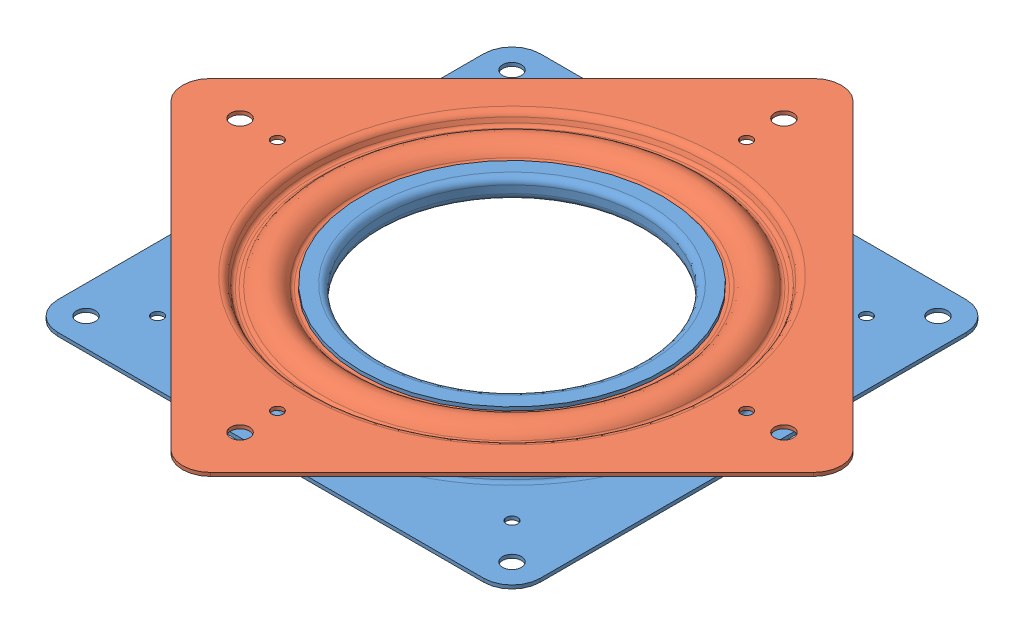
SolidWorks assembly Lazy Susan Bearing, configuration Default. Lengths in mm.
Overall size (143.68 8.13 143.68).
38 component instances, 3 part files, 0 mates.
Components (placement in the parent):
- Lazy Susan Bearing_Locking Race-1: Lazy Susan Bearing_Locking Race [Default] at (0 3.0226 0) x (1 0 0) z (0 0 -1) size (101.6 6.63 101.6)
- Lazy Susan Bearing_Plain Race-1: Lazy Susan Bearing_Plain Race [Default] at (0 5.1054 0) x (-0.707107 0 -0.707107) z (0.707107 0 -0.707107) size (101.6 3.03 101.6)
- Lazy Susan Bearing_Ball-1: Lazy Susan Bearing_Ball [Default] at (36.5125 4.064 0) size (6.35 6.35 6.35)
- Lazy Susan Bearing_Ball-2: Lazy Susan Bearing_Ball [Default] at (35.9578 4.064 6.3403) x (0.984808 0 0.173648) z (-0.173648 0 0.984808) size (6.35 6.35 6.35)
- Lazy Susan Bearing_Ball-3: Lazy Susan Bearing_Ball [Default] at (34.3105 4.064 12.488) x (0.939693 0 0.34202) z (-0.34202 0 0.939693) size (6.35 6.35 6.35)
- Lazy Susan Bearing_Ball-4: Lazy Susan Bearing_Ball [Default] at (31.6208 4.064 18.2563) x (0.866025 0 0.5) z (-0.5 0 0.866025) size (6.35 6.35 6.35)
- Lazy Susan Bearing_Ball-5: Lazy Susan Bearing_Ball [Default] at (27.9702 4.064 23.4698) x (0.766044 0 0.642788) z (-0.642788 0 0.766044) size (6.35 6.35 6.35)
- Lazy Susan Bearing_Ball-6: Lazy Susan Bearing_Ball [Default] at (23.4698 4.064 27.9702) x (0.642788 0 0.766044) z (-0.766044 0 0.642788) size (6.35 6.35 6.35)
- Lazy Susan Bearing_Ball-7: Lazy Susan Bearing_Ball [Default] at (18.2563 4.064 31.6208) x (0.5 0 0.866025) z (-0.866025 0 0.5) size (6.35 6.35 6.35)
- Lazy Susan Bearing_Ball-8: Lazy Susan Bearing_Ball [Default] at (12.488 4.064 34.3105) x (0.34202 0 0.939693) z (-0.939693 0 0.34202) size (6.35 6.35 6.35)
- Lazy Susan Bearing_Ball-9: Lazy Susan Bearing_Ball [Default] at (6.3403 4.064 35.9578) x (0.173648 0 0.984808) z (-0.984808 0 0.173648) size (6.35 6.35 6.35)
- Lazy Susan Bearing_Ball-10: Lazy Susan Bearing_Ball [Default] at (0 4.064 36.5125) x (0 0 1) z (-1 0 0) size (6.35 6.35 6.35)
- Lazy Susan Bearing_Ball-11: Lazy Susan Bearing_Ball [Default] at (-6.3403 4.064 35.9578) x (-0.173648 0 0.984808) z (-0.984808 0 -0.173648) size (6.35 6.35 6.35)
- Lazy Susan Bearing_Ball-12: Lazy Susan Bearing_Ball [Default] at (-12.488 4.064 34.3105) x (-0.34202 0 0.939693) z (-0.939693 0 -0.34202) size (6.35 6.35 6.35)
- Lazy Susan Bearing_Ball-13: Lazy Susan Bearing_Ball [Default] at (-18.2563 4.064 31.6208) x (-0.5 0 0.866025) z (-0.866025 0 -0.5) size (6.35 6.35 6.35)
- Lazy Susan Bearing_Ball-14: Lazy Susan Bearing_Ball [Default] at (-23.4698 4.064 27.9702) x (-0.642788 0 0.766044) z (-0.766044 0 -0.642788) size (6.35 6.35 6.35)
- Lazy Susan Bearing_Ball-15: Lazy Susan Bearing_Ball [Default] at (-27.9702 4.064 23.4698) x (-0.766044 0 0.642788) z (-0.642788 0 -0.766044) size (6.35 6.35 6.35)
- Lazy Susan Bearing_Ball-16: Lazy Susan Bearing_Ball [Default] at (-31.6208 4.064 18.2563) x (-0.866025 0 0.5) z (-0.5 0 -0.866025) size (6.35 6.35 6.35)
- Lazy Susan Bearing_Ball-17: Lazy Susan Bearing_Ball [Default] at (-34.3105 4.064 12.488) x (-0.939693 0 0.34202) z (-0.34202 0 -0.939693) size (6.35 6.35 6.35)
- Lazy Susan Bearing_Ball-18: Lazy Susan Bearing_Ball [Default] at (-35.9578 4.064 6.3403) x (-0.984808 0 0.173648) z (-0.173648 0 -0.984808) size (6.35 6.35 6.35)
- Lazy Susan Bearing_Ball-19: Lazy Susan Bearing_Ball [Default] at (-36.5125 4.064 0) x (-1 0 0) z (0 0 -1) size (6.35 6.35 6.35)
- Lazy Susan Bearing_Ball-20: Lazy Susan Bearing_Ball [Default] at (-35.9578 4.064 -6.3403) x (-0.984808 0 -0.173648) z (0.173648 0 -0.984808) size (6.35 6.35 6.35)
- Lazy Susan Bearing_Ball-21: Lazy Susan Bearing_Ball [Default] at (-34.3105 4.064 -12.488) x (-0.939693 0 -0.34202) z (0.34202 0 -0.939693) size (6.35 6.35 6.35)
- Lazy Susan Bearing_Ball-22: Lazy Susan Bearing_Ball [Default] at (-31.6208 4.064 -18.2563) x (-0.866025 0 -0.5) z (0.5 0 -0.866025) size (6.35 6.35 6.35)
- Lazy Susan Bearing_Ball-23: Lazy Susan Bearing_Ball [Default] at (-27.9702 4.064 -23.4698) x (-0.766044 0 -0.642788) z (0.642788 0 -0.766044) size (6.35 6.35 6.35)
- Lazy Susan Bearing_Ball-24: Lazy Susan Bearing_Ball [Default] at (-23.4698 4.064 -27.9702) x (-0.642788 0 -0.766044) z (0.766044 0 -0.642788) size (6.35 6.35 6.35)
- Lazy Susan Bearing_Ball-25: Lazy Susan Bearing_Ball [Default] at (-18.2563 4.064 -31.6208) x (-0.5 0 -0.866025) z (0.866025 0 -0.5) size (6.35 6.35 6.35)
- Lazy Susan Bearing_Ball-26: Lazy Susan Bearing_Ball [Default] at (-12.488 4.064 -34.3105) x (-0.34202 0 -0.939693) z (0.939693 0 -0.34202) size (6.35 6.35 6.35)
- Lazy Susan Bearing_Ball-27: Lazy Susan Bearing_Ball [Default] at (-6.3403 4.064 -35.9578) x (-0.173648 0 -0.984808) z (0.984808 0 -0.173648) size (6.35 6.35 6.35)
- Lazy Susan Bearing_Ball-28: Lazy Susan Bearing_Ball [Default] at (0 4.064 -36.5125) x (0 0 -1) z (1 0 0) size (6.35 6.35 6.35)
- Lazy Susan Bearing_Ball-29: Lazy Susan Bearing_Ball [Default] at (6.3403 4.064 -35.9578) x (0.173648 0 -0.984808) z (0.984808 0 0.173648) size (6.35 6.35 6.35)
- Lazy Susan Bearing_Ball-30: Lazy Susan Bearing_Ball [Default] at (12.488 4.064 -34.3105) x (0.34202 0 -0.939693) z (0.939693 0 0.34202) size (6.35 6.35 6.35)
- Lazy Susan Bearing_Ball-31: Lazy Susan Bearing_Ball [Default] at (18.2563 4.064 -31.6208) x (0.5 0 -0.866025) z (0.866025 0 0.5) size (6.35 6.35 6.35)
- Lazy Susan Bearing_Ball-32: Lazy Susan Bearing_Ball [Default] at (23.4698 4.064 -27.9702) x (0.642788 0 -0.766044) z (0.766044 0 0.642788) size (6.35 6.35 6.35)
- Lazy Susan Bearing_Ball-33: Lazy Susan Bearing_Ball [Default] at (27.9702 4.064 -23.4698) x (0.766044 0 -0.642788) z (0.642788 0 0.766044) size (6.35 6.35 6.35)
- Lazy Susan Bearing_Ball-34: Lazy Susan Bearing_Ball [Default] at (31.6208 4.064 -18.2563) x (0.866025 0 -0.5) z (0.5 0 0.866025) size (6.35 6.35 6.35)
- Lazy Susan Bearing_Ball-35: Lazy Susan Bearing_Ball [Default] at (34.3105 4.064 -12.488) x (0.939693 0 -0.34202) z (0.34202 0 0.939693) size (6.35 6.35 6.35)
- Lazy Susan Bearing_Ball-36: Lazy Susan Bearing_Ball [Default] at (35.9578 4.064 -6.3403) x (0.984808 0 -0.173648) z (0.173648 0 0.984808) size (6.35 6.35 6.35)
